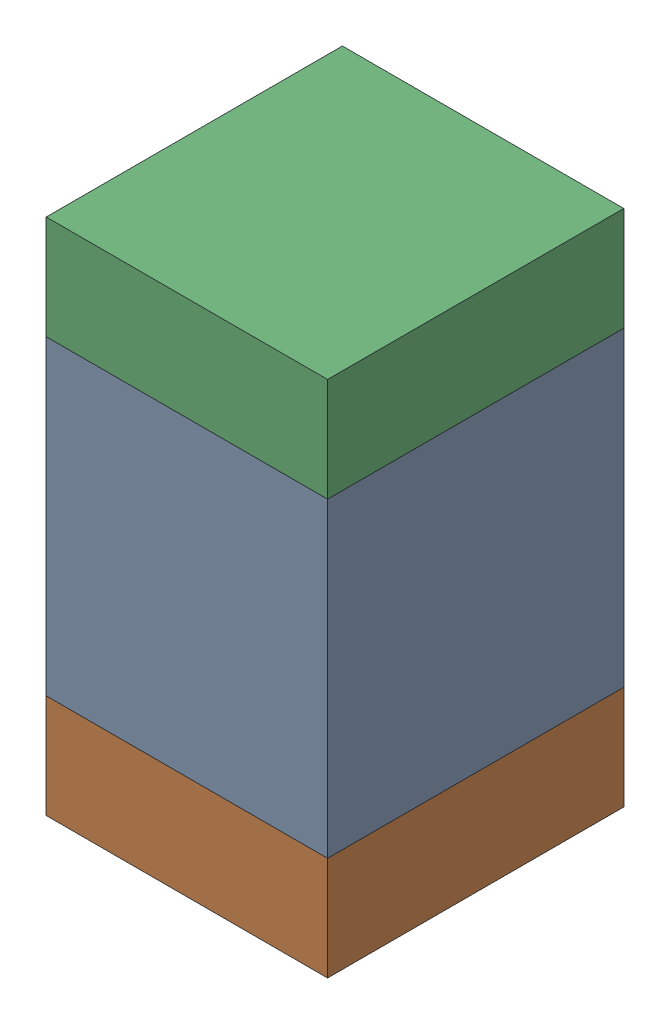
SolidWorks assembly C308_1PCB, configuration Default. Lengths in mm.
Overall size (0.95 1.75 1).
6 component instances, 2 part files, 0 mates.
Components (placement in the parent):
- 761616384-1: 761616384 [Default] at (124.0343 113.35 0) size (0.95 1.05 1)
  - Extruded_5-1: Extruded_5 [Default] at origin size (0.95 1.05 1)
- 761616520-1: 761616520 [Default] at (124.0343 112.65 0) size (0.95 0.35 1)
  - Extruded_6-1: Extruded_6 [Default] at origin size (0.95 0.35 1)
- 761616520-2: 761616520 [Default] at (124.0343 114.05 0) size (0.95 0.35 1)
  - Extruded_6-1: Extruded_6 [Default] at origin size (0.95 0.35 1)
